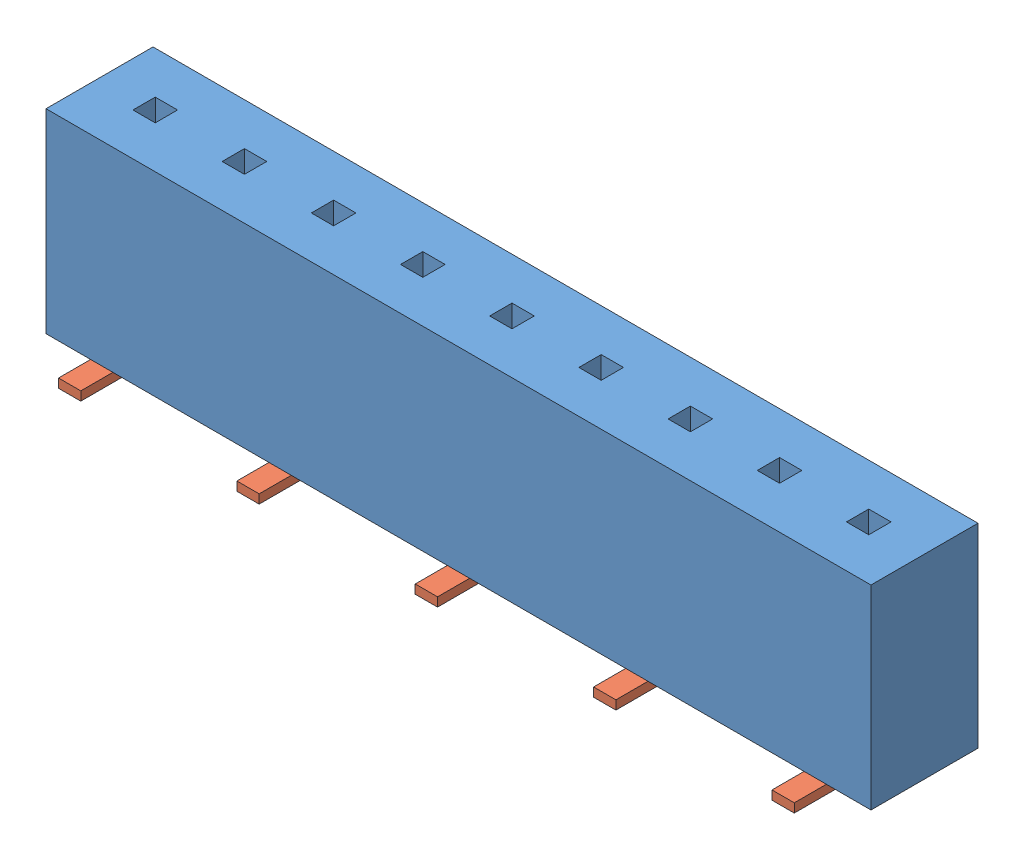
SolidWorks assembly connector.2mm.09-pin.female.surface-mount, configuration Default. Lengths in mm.
Overall size (18.5 4.57 3.84).
10 component instances, 2 part files, 0 mates.
Components (placement in the parent):
- connector.2mm.09-pin.male.2-1: connector.2mm.09-pin.male.2 [Default] at (0 0.2 0) size (18.5 4.37 2.4)
- surface-mount-2mm-pin-socket-tab-1: surface-mount-2mm-pin-socket-tab [Default] at (0.75 0 -1.25) x (0 0 1) z (-1 0 0) size (2.17 0.2 0.5)
- surface-mount-2mm-pin-socket-tab-2: surface-mount-2mm-pin-socket-tab [Default] at (3.25 0 -0.75) x (0 0 -1) z (1 0 0) size (2.17 0.2 0.5)
- surface-mount-2mm-pin-socket-tab-3: surface-mount-2mm-pin-socket-tab [Default] at (4.75 0 -1.25) x (0 0 1) z (-1 0 0) size (2.17 0.2 0.5)
- surface-mount-2mm-pin-socket-tab-4: surface-mount-2mm-pin-socket-tab [Default] at (8.75 0 -1.25) x (0 0 1) z (-1 0 0) size (2.17 0.2 0.5)
- surface-mount-2mm-pin-socket-tab-5: surface-mount-2mm-pin-socket-tab [Default] at (12.75 0 -1.25) x (0 0 1) z (-1 0 0) size (2.17 0.2 0.5)
- surface-mount-2mm-pin-socket-tab-6: surface-mount-2mm-pin-socket-tab [Default] at (16.75 0 -1.25) x (0 0 1) z (-1 0 0) size (2.17 0.2 0.5)
- surface-mount-2mm-pin-socket-tab-7: surface-mount-2mm-pin-socket-tab [Default] at (7.25 0 -0.75) x (0 0 -1) z (1 0 0) size (2.17 0.2 0.5)
- surface-mount-2mm-pin-socket-tab-8: surface-mount-2mm-pin-socket-tab [Default] at (11.25 0 -0.75) x (0 0 -1) z (1 0 0) size (2.17 0.2 0.5)
- surface-mount-2mm-pin-socket-tab-9: surface-mount-2mm-pin-socket-tab [Default] at (15.25 0 -0.75) x (0 0 -1) z (1 0 0) size (2.17 0.2 0.5)
